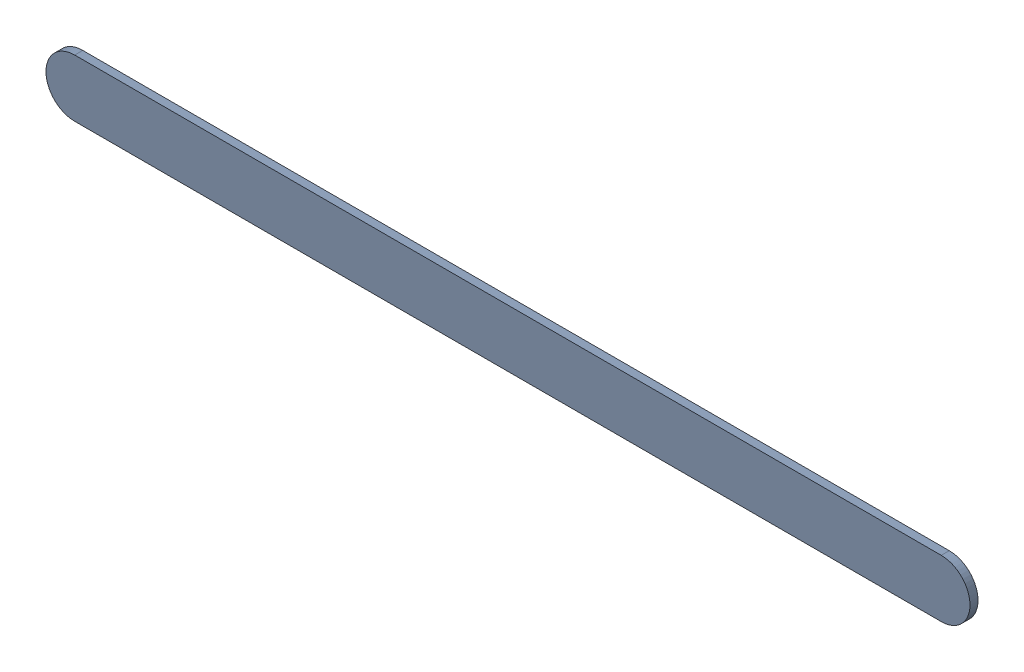
SolidWorks assembly Track (21.267mm,47.493mm)(25.1mm,47.493mm) on Bottom Layer, configuration Predeterminado. Lengths in mm.
Overall size (4.09 0.25 0.04).
2 component instances, 1 part files, 0 mates.
Components (placement in the parent):
- Track (21.267mm,47.493mm)(25.1mm,47.493mm) on Bottom Layer-1-1: Track (21.267mm,47.493mm)(25.1mm,47.493mm) on Bottom Layer-1 [Predeterminado] at (-68.317 -44.187 -0.4013) size (4.09 0.25 0.04)
  - Track (21.267mm,47.493mm)(25.1mm,47.493mm) on Bottom Layer-Part-1-1: Track (21.267mm,47.493mm)(25.1mm,47.493mm) on Bottom Layer-Part-1 [Predeterminado] at origin size (4.09 0.25 0.04)
